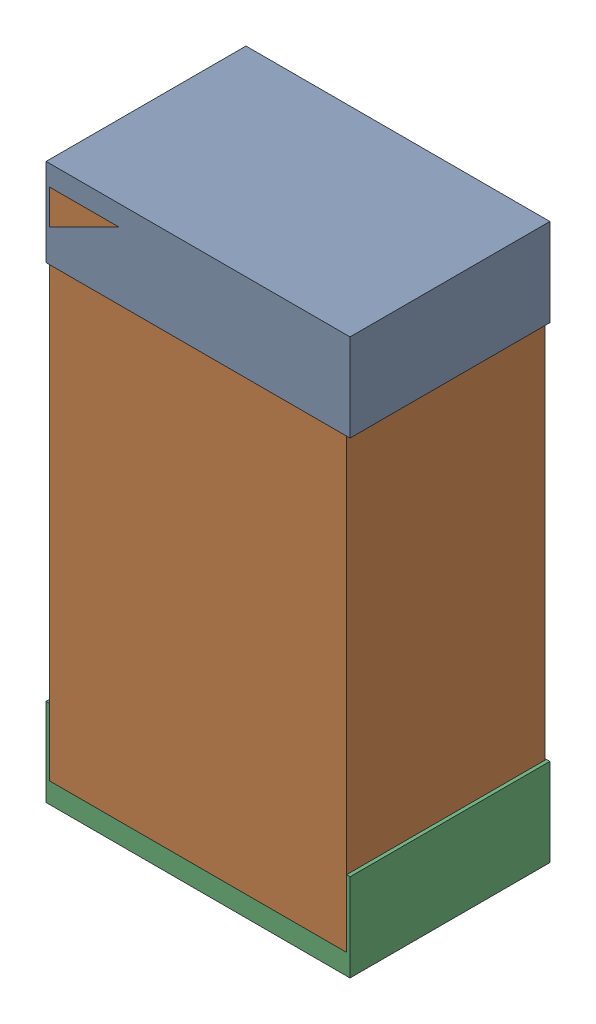
SolidWorks assembly R37Kanaloa_v2.0.0_Motor, configuration Default. Lengths in mm.
Overall size (1.3 2.38 0.85).
6 component instances, 2 part files, 0 mates.
Components (placement in the parent):
- 330415056-1: 330415056 [Default] at (39.116 120.634 -1.9574) size (1.3 0.38 0.85)
  - Extruded_2-1: Extruded_2 [Default] at origin size (1.3 0.38 0.85)
- 334787376-1: 334787376 [Default] at (39.116 119.634 -1.9524) size (1.27 2.2 0.85)
  - Extruded_16-1: Extruded_16 [Default] at origin size (1.27 2.2 0.85)
- 330415056-2: 330415056 [Default] at (39.116 118.634 -1.9574) size (1.3 0.38 0.85)
  - Extruded_2-1: Extruded_2 [Default] at origin size (1.3 0.38 0.85)
